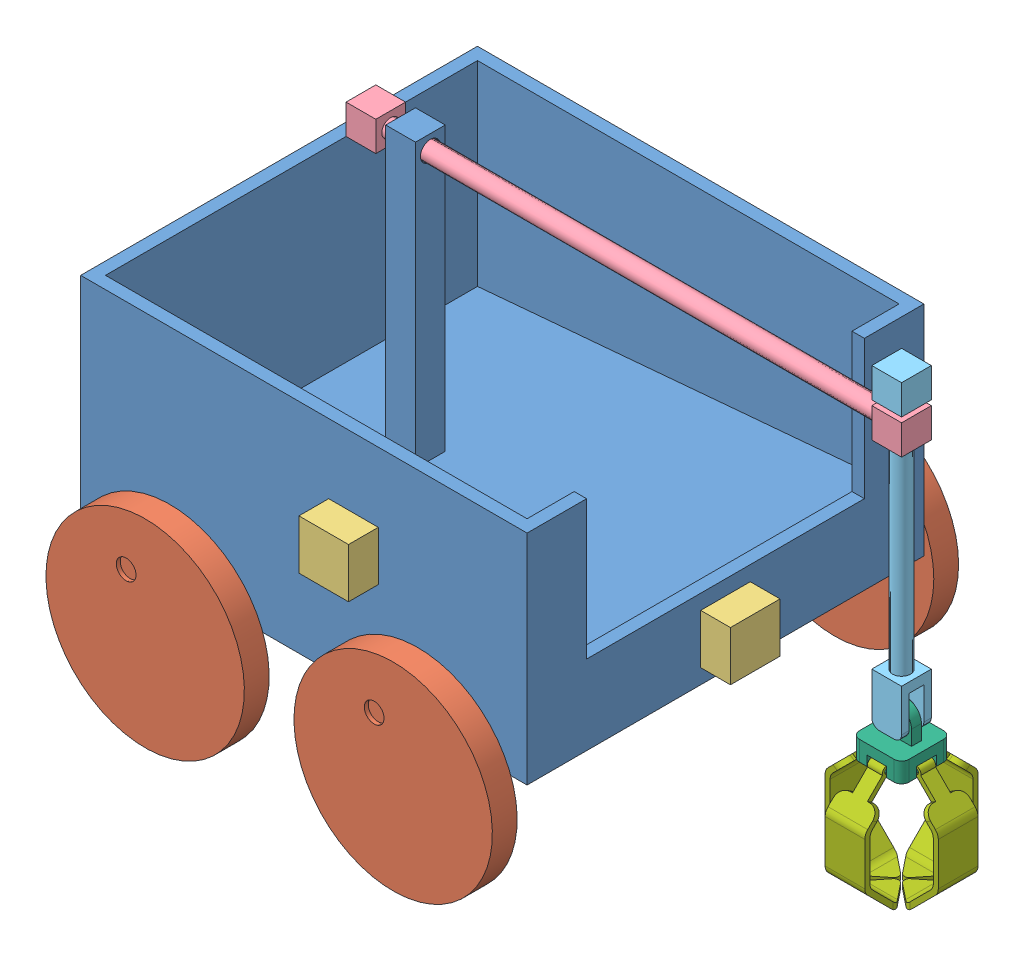
SolidWorks assembly BOT5, configuration Default. Lengths in mm.
Overall size (715.23 510.68 470).
15 component instances, 7 part files, 37 mates.
Components (placement in the parent):
- Base-1: Base [Default] at origin size (450 370 400)
- Wheel-1: Wheel [Default] at (125 -25 -235) size (200 200 105)
- Wheel-2: Wheel [Default] at (-125 -25 -235) size (200 200 105)
- Wheel-3: Wheel [Default] at (-125 -25 235) x (-0.923728 -0.383049 0) z (0 0 -1) size (200 200 105)
- Wheel-4: Wheel [Default] at (125 -25 235) x (-0.923728 -0.383049 0) z (0 0 -1) size (200 200 105)
- Camera-1: Camera [Default] at (50 125 230) x (0 0 -1) z (1 0 0) size (30 50 50)
- Camera-2: Camera [Default] at (50 125 -200) x (0 0 -1) z (1 0 0) size (30 50 50)
- Camera-3: Camera [Default] at (225 40 0) size (30 50 50)
- Extension Pole 1-1: Extension Pole 1 [Default] at (-142.5 305 0) size (560 30 30)
- Extension Pole 2-1: Extension Pole 2 [Default] at (402.5 355 0) x (-1 0 0) z (0 0 1) size (30 315 30)
- Claw holder-1: Claw holder [Default] at (402.5 32.5 0) size (50 100 50)
- Angular Finger-1: Angular Finger [Default] at (402.5 -37.5 0) x (0 0 1) z (-1 0 0) size (54.05 118 40)
- Angular Finger-2: Angular Finger [Default] at (402.5 -37.5 0) size (54.05 118 40)
- Angular Finger-3: Angular Finger [Default] at (402.5 -37.5 0) x (0 0 -1) z (1 0 0) size (54.05 118 40)
- Angular Finger-4: Angular Finger [Default] at (402.5 -37.5 0) x (-1 0 0) z (0 0 -1) size (54.05 118 40)
Mates (geometry in assembly coordinates):
- Concentric1: concentric aligned: cylinder of Base-1 through (-125 -25 -132.5736) axis (0 0 -1) radius 15; cylinder of Wheel-2 through (-125 -25 -130) axis (0 0 -1) radius 14
- Distance1: distance = 10 mm anti-aligned: plane of Wheel-2 through (-125 -25 -210) normal (0 0 1); plane of Base-1 through (-225 220 -200) normal (0 0 -1)
- Concentric2: concentric aligned: cylinder of Base-1 through (-125 -25 132.5736) axis (0 0 1) radius 15; cylinder of Wheel-3 through (-125 -25 130) axis (0 0 1) radius 14
- Distance2: distance = 10 mm anti-aligned: plane of Base-1 through (-225 220 200) normal (0 0 1); plane of Wheel-3 through (-125 -25 210) normal (0 0 -1)
- Concentric5: concentric aligned: cylinder of Base-1 through (125 -25 132.5736) axis (0 0 1) radius 15; cylinder of Wheel-4 through (125 -25 130) axis (0 0 1) radius 14
- Distance4: distance = 10 mm anti-aligned: plane of Base-1 through (-225 220 200) normal (0 0 1); plane of Wheel-4 through (125 -25 210) normal (0 0 -1)
- Concentric6: concentric aligned: cylinder of Base-1 through (125 -25 -132.5736) axis (0 0 -1) radius 15; cylinder of Wheel-1 through (125 -25 -130) axis (0 0 -1) radius 14
- Distance5: distance = 10 mm anti-aligned: plane of Base-1 through (-225 220 -200) normal (0 0 -1); plane of Wheel-1 through (125 -25 -210) normal (0 0 1)
- Concentric7: concentric anti-aligned: cylinder of Base-1 through (-102.5 305 0) axis (1 0 0) radius 10; cylinder of Extension Pole 1-1 through (387.5 305 0) axis (-1 0 0) radius 9
- Concentric8: concentric aligned: cylinder of Extension Pole 1-1 through (402.5 261.7157 0) axis (0 1 0) radius 10; cylinder of Extension Pole 2-1 through (402.5 90 0) axis (0 1 0) radius 9
- Coincident5: coincident aligned: plane of Base-1 through (-102.5 320 15) normal (0 0 1); plane of Extension Pole 2-1 through (417.5 325 15) normal (0 0 1)
- Coincident6: coincident anti-aligned: plane of Base-1 through (225 220 -200) normal (1 0 0); plane of Camera-3 through (225 40 0) normal (-1 0 0)
- Distance6: distance = 15 mm aligned: plane of Camera-3 through (255 15 25) normal (0 -1 0); plane of Base-1 through (0 0 0) normal (0 -1 0)
- Distance7: distance = 175 mm aligned: plane of Camera-3 through (255 65 -25) normal (0 0 -1); plane of Base-1 through (-225 220 -200) normal (0 0 -1)
- Coincident9: coincident anti-aligned: plane of Base-1 through (-225 220 200) normal (0 0 1); plane of Camera-1 through (50 125 200) normal (0 0 -1)
- Distance8: distance = 100 mm aligned: plane of Camera-1 through (75 100 200) normal (0 -1 0); plane of Base-1 through (0 0 0) normal (0 -1 0)
- Distance9: distance = 150 mm aligned: plane of Camera-1 through (75 150 200) normal (1 0 0); plane of Base-1 through (225 220 -200) normal (1 0 0)
- Coincident12: coincident anti-aligned: plane of Base-1 through (-225 220 -200) normal (0 0 -1); plane of Camera-2 through (50 125 -200) normal (0 0 1)
- Distance10: distance = 100 mm aligned: plane of Camera-2 through (75 100 -230) normal (0 -1 0); plane of Base-1 through (0 0 0) normal (0 -1 0)
- Distance11: distance = 150 mm aligned: plane of Base-1 through (225 220 -200) normal (1 0 0); plane of Camera-2 through (75 150 -230) normal (1 0 0)
- Concentric9: concentric anti-aligned: cylinder of Claw holder-1 through (424.5 15.5 -14.2426) axis (0 0 1) radius 1.5; cylinder of Angular Finger-2 through (424.5 15.5 20) axis (0 0 -1) radius 2.5
- Distance12: distance = 2.5 mm anti-aligned: plane of Claw holder-1 through (427.5 22.5 10) normal (0 0 -1); plane of Angular Finger-2 through (402.5 -37.5 7.5) normal (0 0 1)
- Concentric10: concentric anti-aligned: cylinder of Claw holder-1 through (416.7426 15.5 22) axis (-1 0 0) radius 1.5; cylinder of Angular Finger-1 through (382.5 15.5 22) axis (1 0 0) radius 2.5
- Distance13: distance = 2.5 mm anti-aligned: plane of Claw holder-1 through (392.5 22.5 25) normal (1 0 0); plane of Angular Finger-1 through (395 -37.5 0) normal (-1 0 0)
- Concentric11: concentric aligned: cylinder of Claw holder-1 through (380.5 15.5 -14.2426) axis (0 0 1) radius 1.5; cylinder of Angular Finger-4 through (380.5 15.5 -20) axis (0 0 1) radius 2.5
- Distance14: distance = 2.5 mm anti-aligned: plane of Claw holder-1 through (377.5 22.5 -10) normal (0 0 1); plane of Angular Finger-4 through (402.5 -37.5 -7.5) normal (0 0 -1)
- Concentric12: concentric anti-aligned: cylinder of Claw holder-1 through (388.2574 15.5 -22) axis (1 0 0) radius 1.5; cylinder of Angular Finger-3 through (422.5 15.5 -22) axis (-1 0 0) radius 2.5
- Distance15: distance = 2.5 mm anti-aligned: plane of Claw holder-1 through (412.5 22.5 -25) normal (-1 0 0); plane of Angular Finger-3 through (410 -37.5 0) normal (1 0 0)
- LimitAngle1: limit planar angle = 2.356194 rad anti-aligned: plane of Angular Finger-2 through (441.7678 1.7678 20) normal (0.707107 0.707107 0); plane of Claw holder-1 through (427.5 12.5 25) normal (1 0 0)
- LimitAngle2: limit planar angle = 2.356194 rad anti-aligned: plane of Angular Finger-1 through (382.5 1.7678 39.2678) normal (0 0.707107 0.707107); plane of Claw holder-1 through (377.5 12.5 25) normal (0 0 1)
- LimitAngle3: limit planar angle = 2.356194 rad anti-aligned: plane of Claw holder-1 through (377.5 12.5 -25) normal (0 0 -1); plane of Angular Finger-3 through (422.5 1.7678 -39.2678) normal (0 0.707107 -0.707107)
- LimitAngle4: limit planar angle = 2.356194 rad anti-aligned: plane of Angular Finger-4 through (363.2322 1.7678 -20) normal (-0.707107 0.707107 0); plane of Claw holder-1 through (377.5 12.5 25) normal (-1 0 0)
- Concentric13: concentric aligned: cylinder of Extension Pole 2-1 through (402.5 52.5 -28.7132) axis (0 0 1) radius 7.5; cylinder of Claw holder-1 through (402.5 52.5 -27.6274) axis (0 0 1) radius 8
- LimitDistance2: limit distance = 10 mm anti-aligned: plane of Extension Pole 1-1 through (-112.5 305 0) normal (1 0 0); plane of Base-1 through (-102.5 320 -15) normal (-1 0 0)
- LimitDistance3: limit distance = 5 mm anti-aligned: plane of Extension Pole 1-1 through (417.5 320 15) normal (0 1 0); plane of Extension Pole 2-1 through (402.5 325 0) normal (0 -1 0)
- Distance17: distance = 2.5 mm anti-aligned: plane of Extension Pole 2-1 through (417.5 80 7.5) normal (0 0 -1); plane of Claw holder-1 through (387.5 62.5 5) normal (0 0 1)
- LimitAngle5: limit planar angle = 1.570796 rad anti-aligned: plane of Extension Pole 2-1 through (417.5 40 -15) normal (1 0 0); plane of Claw holder-1 through (402.5 32.5 0) normal (0 1 0)
